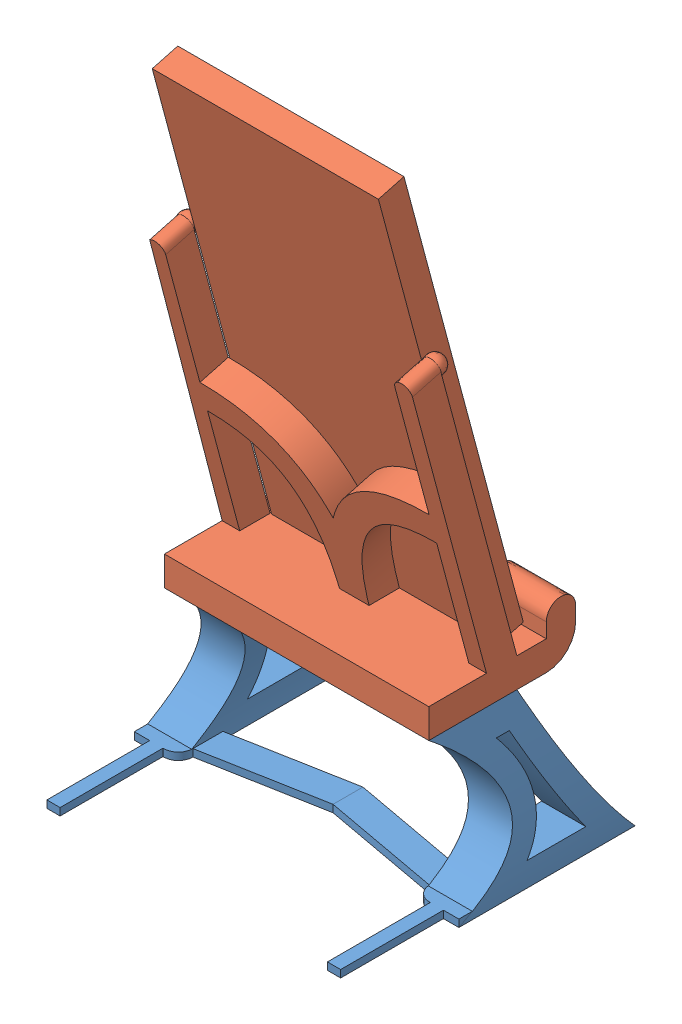
SolidWorks assembly phone_assembly, configuration Domyślna. Lengths in mm.
Overall size (111.03 213.98 95).
2 component instances, 2 part files, 3 mates.
Components (placement in the parent):
- legs-1: legs [Domyślna] at (6.906 -26.7015 110.6) size (111.03 50 95)
- Phone_stand-1: Phone_stand [Domyślna] at (6.906 23.2985 60.6) x (0 0 -1) z (1 0 0) size (60.63 163.98 90.25)
Mates (geometry in assembly coordinates):
- Coincident1: coincident anti-aligned: plane of legs-1 through (6.906 23.2985 110.6) normal (0 1 0); plane of Phone_stand-1 through (6.906 23.2985 60.6) normal (0 -1 0)
- Coincident2: coincident aligned: line of legs-1 through (51.906 23.2985 110.6) axis (0 0 -1); line of Phone_stand-1 through (51.906 23.2985 110.6) axis (0 0 -1)
- Coincident3: coincident aligned: line of legs-1 through (36.906 23.2985 110.6) axis (1 0 0); line of Phone_stand-1 through (-38.094 23.2985 110.6) axis (1 0 0)
